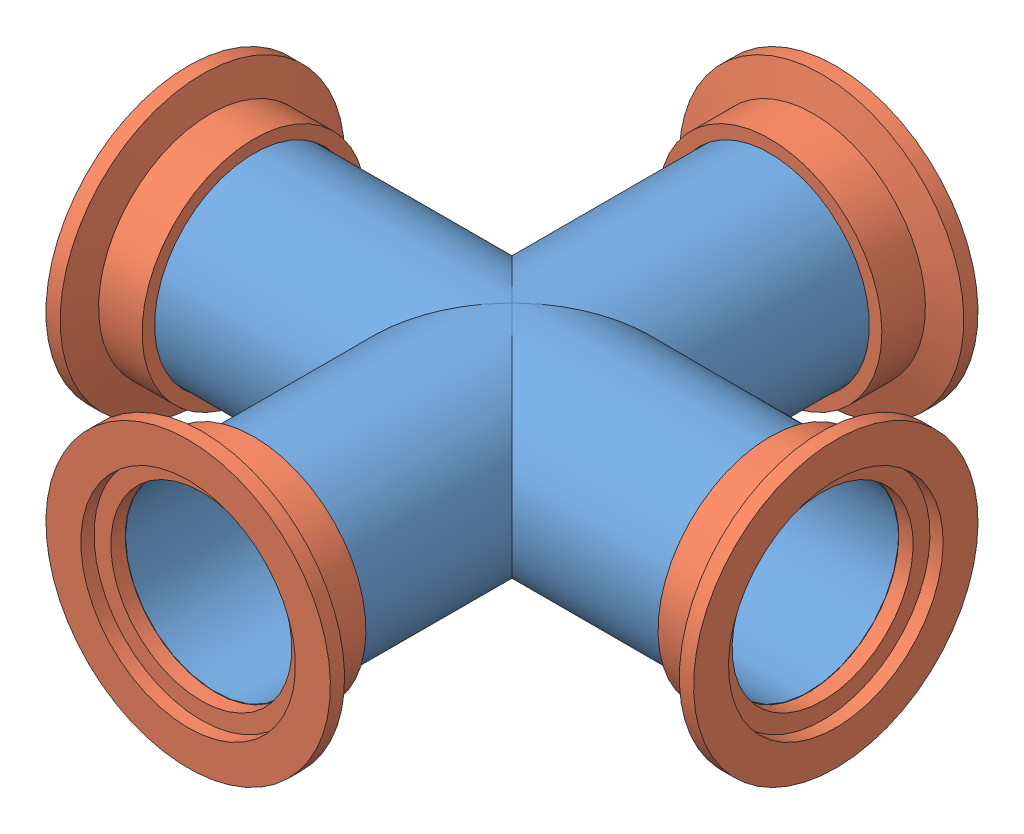
SolidWorks assembly 725002, configuration Default. Lengths in mm.
Overall size (124.92 76.88 124.92).
5 component instances, 2 part files, 8 mates.
Components (placement in the parent):
- 405502-1: 405502 [Default] at (62.1072 54.3505 81.0747) size (114.3 38.1 114.3)
- 713003-99-1: 713003-99 [Default] at (-0.3514 54.3505 81.0747) x (0 -0.588234 0.80869) z (0 -0.80869 -0.588234) size (54.86 12.7 54.86)
- 713003-99-2: 713003-99 [Default] at (62.1072 54.3505 143.5333) x (-1 0 0) z (0 1 0) size (54.86 12.7 54.86)
- 713003-99-3: 713003-99 [Default] at (124.5658 54.3505 81.0747) x (0 0.994639 0.103411) z (0 0.103411 -0.994639) size (54.86 12.7 54.86)
- 713003-99-4: 713003-99 [Default] at (62.1072 54.3505 18.6161) x (-0.796252 -0.604965 0) z (0.604965 -0.796252 0) size (54.86 12.7 54.86)
Mates (geometry in assembly coordinates):
- Coincident1: coincident anti-aligned: plane of 405502-1 through (4.9572 54.3505 81.0747) normal (-1 0 0); plane of 713003-99-1 through (4.9572 43.07 96.583) normal (1 0 0)
- Concentric1: concentric aligned: cylinder of 405502-1 through (119.2572 54.3505 81.0747) axis (-1 0 0) radius 19.05; cylinder of 713003-99-1 through (-0.3514 54.3505 81.0747) axis (-1 0 0) radius 21.59
- Coincident2: coincident anti-aligned: plane of 405502-1 through (62.1072 54.3505 23.9247) normal (0 0 -1); plane of 713003-99-4 through (46.8374 42.7491 23.9247) normal (0 0 1)
- Concentric2: concentric aligned: cylinder of 405502-1 through (62.1072 54.3505 138.2247) axis (0 0 -1) radius 19.05; cylinder of 713003-99-4 through (62.1072 54.3505 18.6161) axis (0 0 -1) radius 21.59
- Coincident3: coincident anti-aligned: plane of 405502-1 through (119.2572 54.3505 81.0747) normal (1 0 0); plane of 713003-99-3 through (119.2572 73.4247 83.0579) normal (-1 0 0)
- Concentric3: concentric anti-aligned: cylinder of 405502-1 through (119.2572 54.3505 81.0747) axis (-1 0 0) radius 19.05; cylinder of 713003-99-3 through (124.5658 54.3505 81.0747) axis (1 0 0) radius 19.177
- Coincident4: coincident anti-aligned: plane of 405502-1 through (62.1072 54.3505 138.2247) normal (0 0 1); plane of 713003-99-2 through (42.9302 54.3505 138.2247) normal (0 0 -1)
- Concentric4: concentric anti-aligned: cylinder of 405502-1 through (62.1072 54.3505 138.2247) axis (0 0 -1) radius 19.05; cylinder of 713003-99-2 through (62.1072 54.3505 143.5333) axis (0 0 1) radius 21.59
